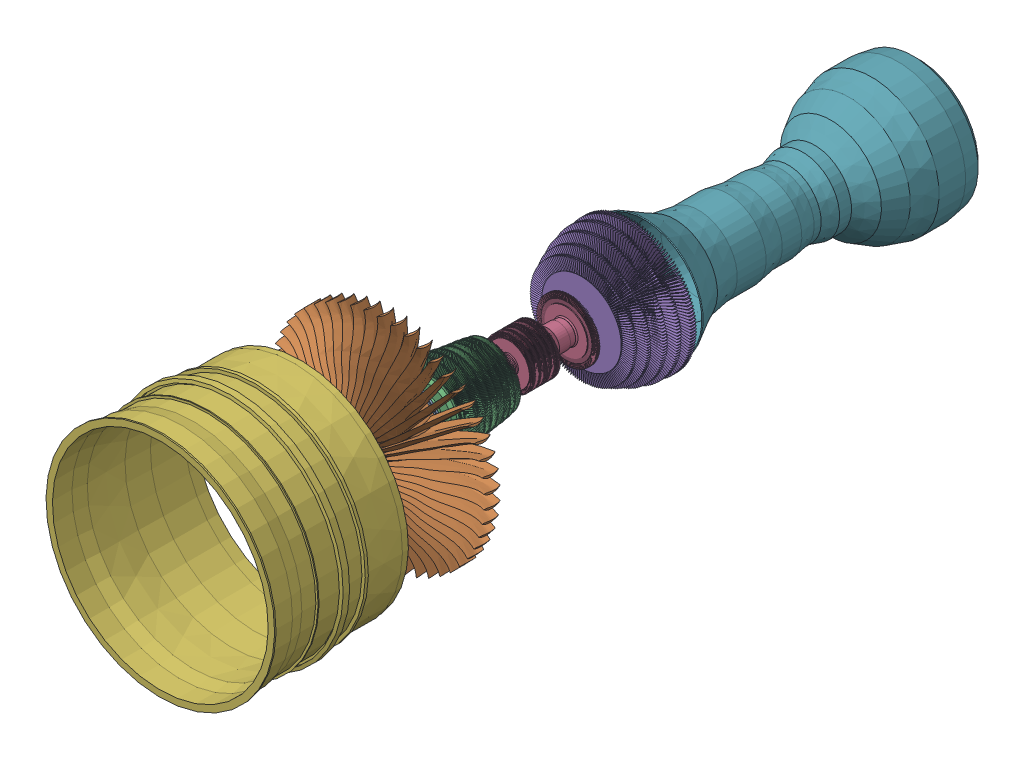
SolidWorks assembly TURBO-ENGINE Assem1, configuration Default. Lengths in mm.
Overall size (3190.35 3190.35 7780.36).
7 component instances, 7 part files, 10 mates.
Components (placement in the parent):
- 1-MINOR PROJECT [AERO-ENGINE MID SHAFT]-1: 1-MINOR PROJECT [AERO-ENGINE MID SHAFT] [Default] at (59.8815 81.3638 2029.9687) size (921.69 921.69 2239.73)
- 1-MINOR PROJECT [AERO-ENGINE FRONT BLADE]-1: 1-MINOR PROJECT [AERO-ENGINE FRONT BLADE] [Default] at (59.8815 81.3638 2029.8604) size (2198.59 2197.33 996.87)
- 1-MINOR PROJECT [AERO-ENGINE TURBINE]-1: 1-MINOR PROJECT [AERO-ENGINE TURBINE] [Default] at (59.8815 81.3638 2242.5318) x (0.982204 0.187818 0) z (0 0 1) size (828.28 828.18 937.03)
- 1-MINOR PROJECT [AERO-ENGINE CC MID]-1: 1-MINOR PROJECT [AERO-ENGINE CC MID] [Default] at (59.8815 81.3638 2252.3195) x (-0.923728 -0.383049 0) z (0 0 1) size (615.79 626.5 839.46)
- 1-MINOR PROJECT [AERO-ENGINE Last part]-1: 1-MINOR PROJECT [AERO-ENGINE Last part] [Default] at (59.8815 81.3638 2410.7122) size (1322.71 1322.7 554.98)
- 1-MINOR PROJECT [AERO-ENGINE COVER FAN]-1: 1-MINOR PROJECT [AERO-ENGINE COVER FAN] [Default] at (59.8815 81.3638 4117.2606) x (-0.874443 -0.485128 0) z (0 0 1) size (2346.59 2346.59 1438.46)
- 1-MINOR PROJECT [AERO-ENGINE COVER TURBINE]-1: 1-MINOR PROJECT [AERO-ENGINE COVER TURBINE] [Default] at (59.8815 81.3638 -230.5712) x (0.588892 -0.808212 0) z (0 0 1) size (1385.68 1385.68 2820.12)
Mates (geometry in assembly coordinates):
- Coincident1: coincident anti-aligned: plane of 1-MINOR PROJECT [AERO-ENGINE MID SHAFT]-1 through (59.8815 81.3638 1032.9889) normal (0 0 1); plane of 1-MINOR PROJECT [AERO-ENGINE FRONT BLADE]-1 through (-260.9308 402.1762 1032.9889) normal (0 0 -1)
- Concentric1: concentric aligned: circle of 1-MINOR PROJECT [AERO-ENGINE MID SHAFT]-1; circle of 1-MINOR PROJECT [AERO-ENGINE FRONT BLADE]-1
- Concentric2: concentric aligned: cone of 1-MINOR PROJECT [AERO-ENGINE MID SHAFT]-1 through (59.8815 81.3638 412.3794) axis (0 0 1); cylinder of 1-MINOR PROJECT [AERO-ENGINE TURBINE]-1 through (59.8815 81.3638 2242.5318) axis (0 0 1) radius 112.5376
- Coincident2: coincident anti-aligned: plane of 1-MINOR PROJECT [AERO-ENGINE MID SHAFT]-1 through (59.8815 189.2265 947.4969) normal (0 0 -1); plane of 1-MINOR PROJECT [AERO-ENGINE TURBINE]-1 through (38.7449 191.8986 947.4969) normal (0 0 1)
- Concentric3: concentric anti-aligned: cylinder of 1-MINOR PROJECT [AERO-ENGINE MID SHAFT]-1 through (59.8815 81.3638 2029.9687) axis (0 0 1) radius 35.6642; cone of 1-MINOR PROJECT [AERO-ENGINE CC MID]-1 through (59.8815 81.3638 10.4645) axis (0 0 -1)
- Coincident3: coincident anti-aligned: plane of 1-MINOR PROJECT [AERO-ENGINE TURBINE]-1 through (49.8013 134.0791 10.4645) normal (0 0 -1); plane of 1-MINOR PROJECT [AERO-ENGINE CC MID]-1 through (85.4869 19.6161 10.4645) normal (0 0 1)
- Concentric4: concentric aligned: cylinder of 1-MINOR PROJECT [AERO-ENGINE MID SHAFT]-1 through (59.8815 81.3638 2029.9687) axis (0 0 1) radius 35.6642; cylinder of 1-MINOR PROJECT [AERO-ENGINE Last part]-1 through (59.8815 81.3638 2410.7122) axis (0 0 1) radius 7.4282
- Coincident4: coincident anti-aligned: plane of 1-MINOR PROJECT [AERO-ENGINE CC MID]-1 through (92.8366 1.8923 -828.9921) normal (0 0 -1); plane of 1-MINOR PROJECT [AERO-ENGINE Last part]-1 through (59.8815 128.7516 -828.9921) normal (0 0 1)
- Concentric5: concentric aligned: cylinder of 1-MINOR PROJECT [AERO-ENGINE CC MID]-1 through (59.8815 81.3638 2252.3195) axis (0 0 1) radius 123.9509; cone of 1-MINOR PROJECT [AERO-ENGINE COVER FAN]-1 through (59.8815 81.3638 959.8861) axis (0 0 1)
- Concentric6: concentric anti-aligned: cylinder of 1-MINOR PROJECT [AERO-ENGINE CC MID]-1 through (59.8815 81.3638 2252.3195) axis (0 0 1) radius 117.307; cone of 1-MINOR PROJECT [AERO-ENGINE COVER TURBINE]-1 through (59.8815 81.3638 1391.1719) axis (0 0 -1)
